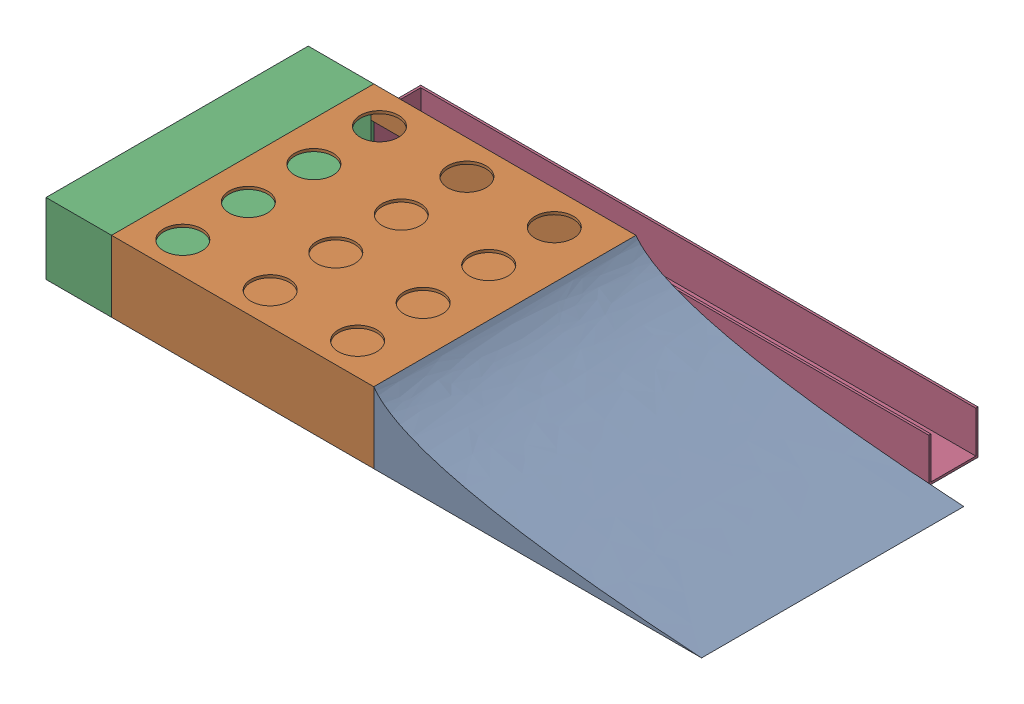
SolidWorks assembly Assem1, configuration Default. Lengths in mm.
Overall size (1524 165.1 723.9).
4 component instances, 4 part files, 12 mates.
Components (placement in the parent):
- ramp-1: ramp [Default] at (112.5621 -82.418 -30.1575) size (762 165.1 609.6)
- HoleBoard-1: HoleBoard [Default] at (-573.2379 0.132 -30.1575) size (609.6 165.1 609.6)
- back_display-1: back_display [Default] at (-878.0379 -82.418 -334.9575) x (0 0 -1) z (1 0 0) size (609.6 165.1 152.4)
- ball reteurn-3: ball reteurn [Default] at (-235.4179 -81.148 -754.0575) x (-1 0 0) z (0 0 -1) size (1295.4 101.6 114.3)
Mates (geometry in assembly coordinates):
- Coincident1: coincident anti-aligned: plane of ramp-1 through (-268.4379 -82.418 -639.7575) normal (-1 0 0); plane of HoleBoard-1 through (-268.4379 -82.418 -639.7575) normal (1 0 0)
- Coincident2: coincident aligned: line of ramp-1 through (-268.4379 -82.418 -639.7575) axis (0 0 1); line of HoleBoard-1 through (-268.4379 -82.418 -639.7575) axis (0 0 1)
- Coincident3: coincident anti-aligned: line of ramp-1 through (-268.4379 82.682 -30.1575) axis (0 -1 0); line of HoleBoard-1 through (-268.4379 -82.418 -30.1575) axis (0 1 0)
- Coincident5: coincident anti-aligned: plane of HoleBoard-1 through (-878.0379 -82.418 -639.7575) normal (-1 0 0); plane of back_display-1 through (-878.0379 -82.418 -334.9575) normal (1 0 0)
- Parallel1: parallel aligned: plane of HoleBoard-1 through (-878.0379 82.682 -639.7575) normal (0 1 0); plane of back_display-1 through (-1030.4379 82.682 -30.1575) normal (0 1 0)
- Parallel2: parallel aligned: plane of HoleBoard-1 through (-573.2379 0.132 -30.1575) normal (0 0 1); plane of back_display-1 through (-1030.4379 -82.418 -30.1575) normal (0 0 1)
- Coincident8: coincident aligned: plane of HoleBoard-1 through (-573.2379 0.132 -30.1575) normal (0 0 1); plane of back_display-1 through (-1030.4379 -82.418 -30.1575) normal (0 0 1)
- Coincident9: coincident aligned: plane of HoleBoard-1 through (-878.0379 -82.418 -639.7575) normal (0 -1 0); plane of back_display-1 through (-1030.4379 -82.418 -30.1575) normal (0 -1 0)
- Parallel4: parallel: plane of HoleBoard-1 through (-789.1379 -76.068 -632.1375) normal (-1 0 0); plane of ball reteurn-3 through (-789.1379 -86.8536 -776.0599) normal (-1 0 0)
- Coincident13: coincident: plane of HoleBoard-1 through (-573.2379 0.132 -639.7575) normal (0 0 -1); plane of ball reteurn-3 through (-235.4179 -91.9336 -639.7575) normal (0 0 1)
- Coincident14: coincident: line of HoleBoard-1 through (-789.1379 12.832 -639.7575) axis (0 -1 0); line of ball reteurn-3 through (-789.1379 -86.8536 -639.7575) axis (0 1 0)
- Coincident15: coincident anti-aligned: line of HoleBoard-1 through (-789.1379 -76.068 -639.7575) axis (-1 0 0); line of ball reteurn-3 through (-878.0379 -86.8536 -639.7575) axis (1 0 0)
